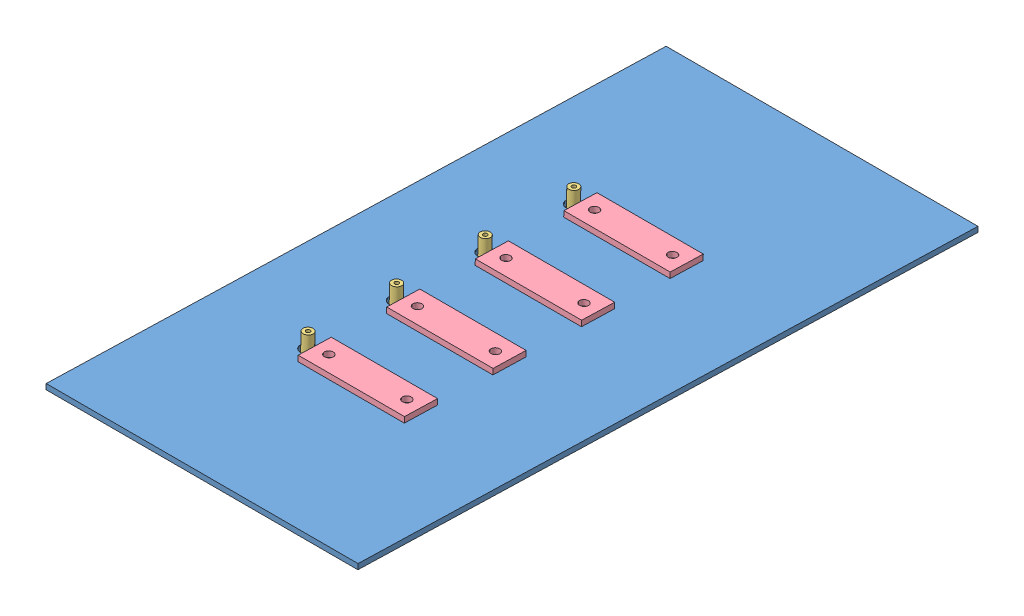
SolidWorks assembly Front_Panel_aluminiumContact_Turtle, configuration Default. Lengths in mm.
Overall size (176 20.62 349.94).
17 component instances, 4 part files, 15 mates.
Components (placement in the parent):
- Body_Front_Panel_aluContact_Turtle-1: Body_Front_Panel_aluContact_Turtle [Default] at (255.1674 288.3056 445.031) x (1 0 0) z (0 0.02885 0.999584) size (176 3 350)
- ContactAluFer-1: ContactAluFer [Default] at (317.0703 243.8583 286.4012) x (1 0 0) z (0 0.02885 0.999584) size (80 15.57 25.3)
  - Contact_barreAlu-1: Contact_barreAlu [Default] at (-13.9029 35.8024 53.6961) size (80 3.2 25.3)
  - ConnecteurAAnneau-1: ConnecteurAAnneau [Default] at (4.0971 39.0024 66.3461) x (0 0 1) z (-1 0 0) size (11.92 12.37 20.64)
  - Contact_barreFer-1: Contact_barreFer [Default] at (-3.9029 42.8524 75.6811) size (60 3.15 18.67)
- ContactAluFer-2: ContactAluFer [Default] at (317.0703 240.9733 186.4428) x (1 0 0) z (0 0.02885 0.999584) size (80 15.57 25.3)
  - Contact_barreAlu-1: Contact_barreAlu [Default] at (-13.9029 35.8024 53.6961) size (80 3.2 25.3)
  - ConnecteurAAnneau-1: ConnecteurAAnneau [Default] at (4.0971 39.0024 66.3461) x (0 0 1) z (-1 0 0) size (11.92 12.37 20.64)
  - Contact_barreFer-1: Contact_barreFer [Default] at (-3.9029 42.8524 75.6811) size (60 3.15 18.67)
- ContactAluFer-3: ContactAluFer [Default] at (317.0703 239.5308 136.4636) x (1 0 0) z (0 0.02885 0.999584) size (80 15.57 25.3)
  - Contact_barreAlu-1: Contact_barreAlu [Default] at (-13.9029 35.8024 53.6961) size (80 3.2 25.3)
  - ConnecteurAAnneau-1: ConnecteurAAnneau [Default] at (4.0971 39.0024 66.3461) x (0 0 1) z (-1 0 0) size (11.92 12.37 20.64)
  - Contact_barreFer-1: Contact_barreFer [Default] at (-3.9029 42.8524 75.6811) size (60 3.15 18.67)
- ContactAluFer-4: ContactAluFer [Default] at (317.0703 242.4158 236.422) x (1 0 0) z (0 0.02885 0.999584) size (80 15.57 25.3)
  - Contact_barreAlu-1: Contact_barreAlu [Default] at (-13.9029 35.8024 53.6961) size (80 3.2 25.3)
  - ConnecteurAAnneau-1: ConnecteurAAnneau [Default] at (4.0971 39.0024 66.3461) x (0 0 1) z (-1 0 0) size (11.92 12.37 20.64)
  - Contact_barreFer-1: Contact_barreFer [Default] at (-3.9029 42.8524 75.6811) size (60 3.15 18.67)
Mates (geometry in assembly coordinates):
- Coincident27: coincident: point of ?
- Parallel2: parallel aligned: line of Contact-1/Part1_contact-1 through (283.1674 283.1413 369.9783) axis (1 0 0)
- Coincident28: coincident: plane of Side_court_avant_turtle-1 through (255.1674 291.3044 444.9444) normal (0 0.999584 -0.02885); plane of ContactAluFer-1/Contact_barreFer-1 through (313.1674 288.8762 360.8144) normal (0 -0.999584 0.02885)
- Coincident41: coincident: unknown of ContactAluFer-1/Contact_barreFer-1
- Coincident42: coincident anti-aligned: line of ContactAluFer-1/Contact_barreFer-1 through (373.1674 288.6069 351.4833) axis (-1 0 0)
- Coincident44: coincident: unknown of ContactAluFer-4/Contact_barreFer-1
- Coincident45: coincident: unknown of ContactAluFer-2/Contact_barreFer-1
- Coincident46: coincident: unknown of ContactAluFer-3/Contact_barreFer-1
- Coincident47: coincident: unknown of ContactAluFer-3/Contact_barreFer-1
- Coincident48: coincident: unknown of ContactAluFer-2/Contact_barreFer-1
- Coincident49: coincident: unknown of ContactAluFer-4/Contact_barreFer-1
- Coincident54: coincident: plane of Side_court_avant_turtle-1 through (255.1674 291.3044 444.9444) normal (0 0.999584 -0.02885); plane of ContactAluFer-4/Contact_barreFer-1 through (313.1674 287.4337 310.8353) normal (0 -0.999584 0.02885)
- Coincident55: coincident: plane of Side_court_avant_turtle-1 through (255.1674 291.3044 444.9444) normal (0 0.999584 -0.02885); plane of ContactAluFer-2/Contact_barreFer-1 through (313.1674 285.9912 260.8561) normal (0 -0.999584 0.02885)
- Coincident56: coincident: plane of Side_court_avant_turtle-1 through (255.1674 291.3044 444.9444) normal (0 0.999584 -0.02885); plane of ContactAluFer-3/Contact_barreFer-1 through (313.1674 284.5487 210.8769) normal (0 -0.999584 0.02885)
- Parallel4: parallel aligned: line of Side_court_avant_turtle-1 through (255.1674 288.3056 445.031) axis (1 0 0); line of ContactAluFer-1/Contact_barreAlu-1 through (303.1674 281.9248 364.3315) axis (1 0 0)
